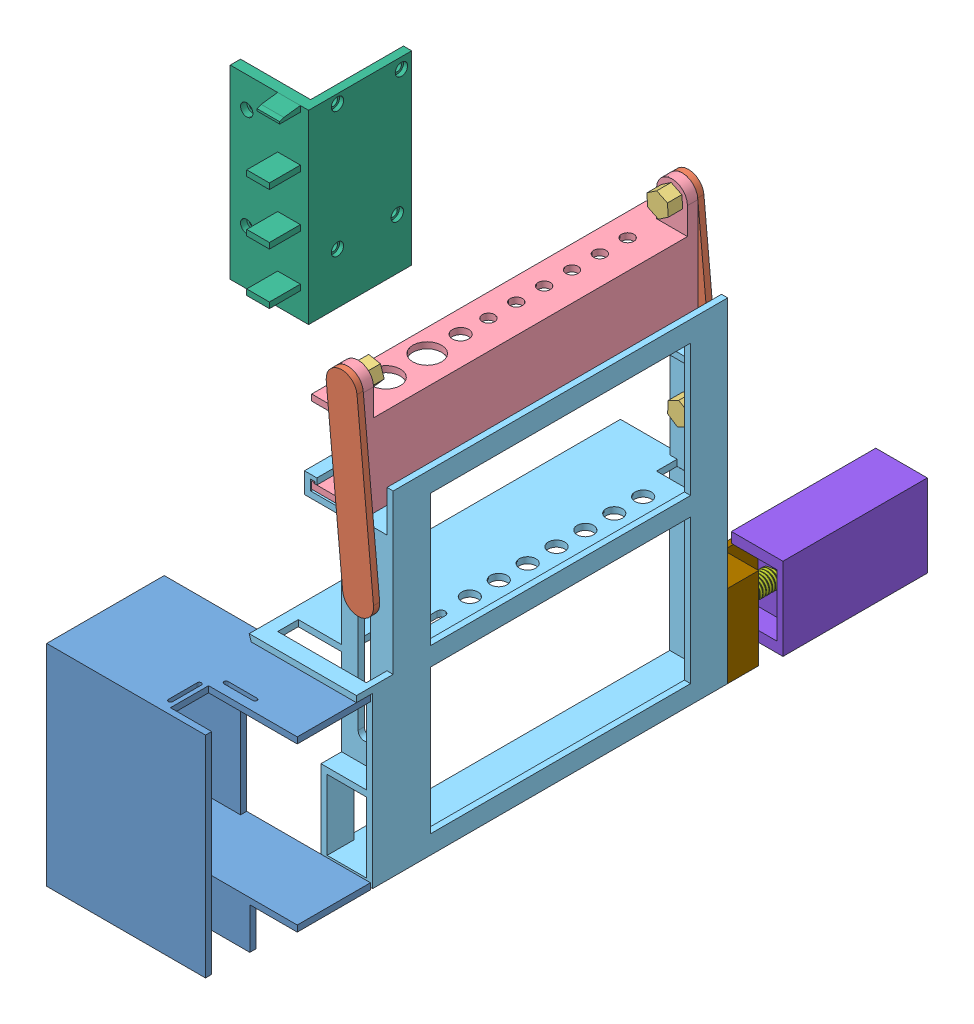
SolidWorks assembly 어셈블리4, configuration 기본. Lengths in mm.
Overall size (367.8 622.9 490.71).
15 component instances, 11 part files, 37 mates.
Components (placement in the parent):
- 식믈부 기둥-1: 식믈부 기둥 [기본] at origin size (390 500 350) (hidden)
- 쿠기스-1: 쿠기스 [기본] at (-51.8638 0 -9.0001) size (390 500 350) (hidden)
- back-1: back [기본] at (93 0 175) x (0 0 -1) z (1 0 0) size (367.8 418.68 100)
- link1-1: link1 [기본] at (186.4667 112.0666 -58.2) x (0 0 1) z (0.995566 0.094063 0) size (10.14 100 15)
- link1-2: link1 [기본] at (171.5333 110.6557 110) x (0 0 -1) z (-0.995566 -0.094063 0) size (10.14 100 15)
- nuttotwo-1: nuttotwo [기본] at (179 111.3611 97) x (0 0 1) z (0.41572 0.909493 0) size (7.19 10.34 11.52)
- nuttotwo-2: nuttotwo [기본] at (179 111.3611 -45.2) x (0 0 -1) z (0.858391 0.512995 0) size (7.19 10.34 11.52)
- nuttotwo-3: nuttotwo [기본] at (171.0047 195.9843 -43.2) x (0 0 -1) z (0.925688 -0.378287 0) size (7.19 10.34 11.52)
- nuttotwo-4: nuttotwo [기본] at (171.0047 195.9843 95) x (0 0 1) z (-0.702957 -0.711233 0) size (7.19 10.34 11.52)
- sensor_holdeRRRRR-1: sensor_holdeRRRRR [기본] at (178.5047 162.9843 107) x (-1 0 0) z (0 0 -1) size (25 60.5 162.2)
- sensore_holderLLLLLL-1: sensore_holderLLLLLL [기본] at (193 135 124.8) x (-1 0 0) z (0 0 -1) size (367.8 418.68 180)
- CO2holder-2: CO2holder [기본] at (195 344.3563 145) x (0 0 1) z (-1 0 0) size (65 90 38)
- longnasa-1: longnasa [기본] at (162.7072 4.0143 8.8) x (0 0 1) z (-0.269661 0.962955 0) size (125 40 25)
- vice-1: vice [기본] at (170 0 -150) x (0 0 -1) z (1 0 0) size (125 40 25)
- sideholder-1: sideholder [기본] at (168 0 -140.2) x (0 0 -1) z (1 0 0) size (85 40 25)
Mates (geometry in assembly coordinates):
- 일치3: coincident aligned: plane of 식믈부 기둥-1 through (0 0 0) normal (0 -1 0); plane of 쿠기스-1 through (-51.8638 0 -9.0001) normal (0 -1 0)
- 일치5: coincident aligned: plane of 식믈부 기둥-1 through (0 500 175) normal (0 0 1); plane of back-1 through (193 82 175) normal (0 0 1)
- 일치7: coincident anti-aligned: plane of 식믈부 기둥-1 through (170 500 0) normal (-1 0 0); plane of back-1 through (170 0 175) normal (1 0 0)
- 일치8: coincident aligned: plane of 식믈부 기둥-1 through (0 0 0) normal (0 -1 0); plane of back-1 through (193 0 175) normal (0 -1 0)
- 일치12: coincident aligned: plane of back-1 through (193 0 175) normal (0 -1 0); plane of sensore_holderLLLLLL-1 through (193 0 -55.2) normal (0 -1 0)
- 일치13: coincident aligned: plane of back-1 through (193 0 175) normal (1 0 0); plane of sensore_holderLLLLLL-1 through (193 85 -55.2) normal (1 0 0)
- 너비2: width aligned: plane of back-1 through (185 68 120) normal (0 0 1); plane of back-1 through (185 68 123) normal (0 0 -1); plane of sensore_holderLLLLLL-1 through (185 78 122.8) normal (0 0 1); plane of sensore_holderLLLLLL-1 through (185 78 120.2) normal (0 0 -1)
- 일치15: coincident anti-aligned: plane of link1-2 through (171.0047 195.9843 107) normal (0 0 -1); plane of sensor_holdeRRRRR-1 through (178.5047 162.9843 107) normal (0 0 1)
- 동심1: concentric anti-aligned: circle of link1-2; circle of sensor_holdeRRRRR-1
- 일치17: coincident anti-aligned: plane of nuttotwo-4 through (171.0047 195.9843 102) normal (0 0 1); plane of sensor_holdeRRRRR-1 through (178.5047 162.9843 102) normal (0 0 -1)
- 동심2: concentric aligned: circle of nuttotwo-4; circle of sensor_holdeRRRRR-1
- 동심3: concentric aligned: cylinder of link1-1 through (171.0047 195.9843 -48.2) axis (0 0 -1) radius 2.4; circle of sensor_holdeRRRRR-1
- 일치19: coincident anti-aligned: plane of link1-1 through (171.0047 195.9843 -55.2) normal (0 0 1); plane of sensor_holdeRRRRR-1 through (178.5047 162.9843 -55.2) normal (0 0 -1)
- 일치20: coincident anti-aligned: plane of nuttotwo-3 through (171.0047 195.9843 -50.2) normal (0 0 -1); plane of sensor_holdeRRRRR-1 through (178.5047 162.9843 -50.2) normal (0 0 1)
- 동심5: concentric anti-aligned: circle of link1-1; circle of nuttotwo-3
- 일치28: coincident anti-aligned: plane of link1-1 through (171.0047 195.9843 -55.2) normal (0 0 1); plane of sensore_holderLLLLLL-1 through (193 135 -55.2) normal (0 0 -1)
- 너비5: width: plane of sensore_holderLLLLLL-1 through (176 129 -45.2) normal (1 0 0); plane of sensore_holderLLLLLL-1 through (182 129 -45.2) normal (-1 0 0); cylinder of link1-1 through (179 111.3611 -48.2) axis (0 0 -1) radius 2.4
- 너비6: width: plane of sensore_holderLLLLLL-1 through (176 53 97) normal (1 0 0); plane of sensore_holderLLLLLL-1 through (182 53 97) normal (-1 0 0); cylinder of link1-2 through (179 111.3611 100) axis (0 0 1) radius 2.4
- 거리 한도3: limit distance = 28.2389 mm: plane of sensore_holderLLLLLL-1 through (193 142 124.8) normal (0 1 0); cylinder of link1-1 through (179 111.3611 -48.2) axis (0 0 -1) radius 2.4
- 거리 한도4: limit distance = 28.2389 mm: plane of sensore_holderLLLLLL-1 through (193 142 124.8) normal (0 1 0); cylinder of link1-2 through (179 111.3611 100) axis (0 0 1) radius 2.4
- 동심6: concentric aligned: cylinder of link1-2 through (179 111.3611 100) axis (0 0 1) radius 2.4; circle of nuttotwo-1
- 일치29: coincident anti-aligned: plane of nuttotwo-1 through (179 111.3611 104) normal (0 0 1); plane of sensore_holderLLLLLL-1 through (193 135 104) normal (0 0 -1)
- 일치31: coincident anti-aligned: plane of nuttotwo-2 through (179 111.3611 -52.2) normal (0 0 -1); plane of sensore_holderLLLLLL-1 through (193 135 -52.2) normal (0 0 1)
- 동심7: concentric anti-aligned: circle of link1-1; circle of nuttotwo-2
- 평행3: parallel aligned: line of 식믈부 기둥-1 through (-195 0 150) axis (0 0 1); line of 쿠기스-1 through (-201.072 2.7756 -136.0001) axis (0 0 1)
- 평행4: parallel aligned: line of 식믈부 기둥-1 through (195 0 -175) axis (-1 0 0); line of 쿠기스-1 through (134.3527 3 -139.0001) axis (-1 0 0)
- 일치39: coincident anti-aligned: plane of 식믈부 기둥-1 through (0 500 150) normal (0 0 -1); plane of CO2holder-2 through (157 344.3563 150) normal (0 0 1)
- 일치40: coincident aligned: plane of 식믈부 기둥-1 through (195 500 0) normal (1 0 0); plane of CO2holder-2 through (195 344.3563 145) normal (1 0 0)
- 일치52: coincident anti-aligned: plane of 식믈부 기둥-1 through (0 500 -150) normal (0 0 1); plane of vice-1 through (195 0 -150) normal (0 0 -1)
- 일치53: coincident aligned: plane of 식믈부 기둥-1 through (0 0 0) normal (0 -1 0); plane of vice-1 through (195 0 -150) normal (0 -1 0)
- 일치54: coincident aligned: plane of 식믈부 기둥-1 through (195 500 0) normal (1 0 0); plane of vice-1 through (195 0 -150) normal (1 0 0)
- 일치55: coincident anti-aligned: plane of sensore_holderLLLLLL-1 through (193 135 -55.2) normal (0 0 -1); plane of sideholder-1 through (168 0 -55.2) normal (0 0 1)
- 일치56: coincident aligned: plane of sensore_holderLLLLLL-1 through (193 85 -55.2) normal (1 0 0); plane of sideholder-1 through (193 0 -55.2) normal (1 0 0)
- 일치57: coincident aligned: plane of vice-1 through (195 40 -150) normal (0 1 0); plane of sideholder-1 through (168 40 -55.2) normal (0 1 0)
- 동심9: concentric aligned: cylinder of longnasa-1 through (179 20 -61.2) axis (0 0 -1) radius 3.8; cylinder of sideholder-1 through (179 20 -61.2) axis (0 0 -1) radius 4
- 일치59: coincident anti-aligned: plane of longnasa-1 through (179 20 -61.2) normal (0 0 1); plane of sideholder-1 through (168 0 -61.2) normal (0 0 -1)
- 평행5: parallel anti-aligned: plane of sensor_holdeRRRRR-1 through (178.5047 142.9843 -55.2) normal (0 -1 0); plane of sensore_holderLLLLLL-1 through (193 142 124.8) normal (0 1 0)
